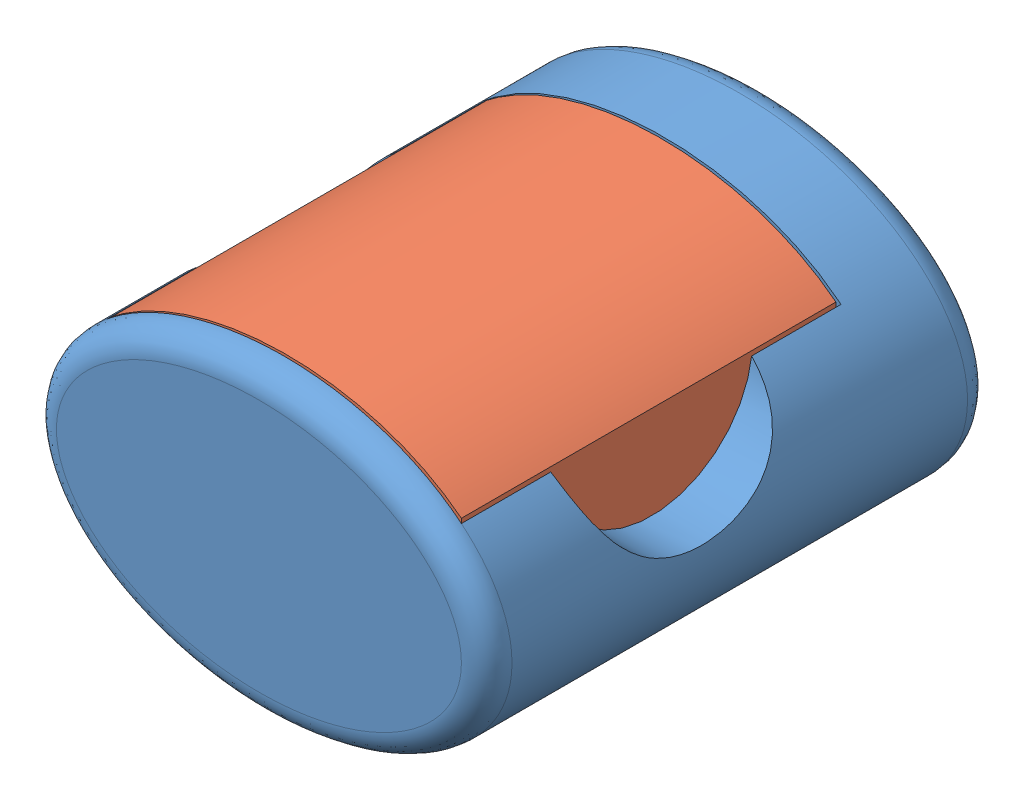
SolidWorks assembly Assem1, configuration Default. Lengths in mm.
Overall size (49.94 34.53 51.77).
31 component instances, 12 part files, 5 mates.
Components (placement in the parent):
- Final Case Bottom-1: Final Case Bottom [Default] at (-38.8329 14.8204 36.3325) size (49.94 34.53 51.77)
- Part2^Assem1-1: Part2^Assem1 [Default] at origin (virtual)
- Final Case Top-1: Final Case Top [Default] at (-38.8329 14.8204 36.3325) size (37.59 19.69 37.59)
- Final Flashlight PCB-1: Final Flashlight PCB [Default] at (-52.8029 8.7956 0.7725) x (1 0 0) z (0 -1 0) size (27.94 31.75 17.34)
  - Board_1-1: Board_1 [Default] at origin size (27.94 31.75 0.41)
  - Imported_1-1: Imported_1 [Default] at origin size (27.76 30.96 17.34)
    - keystone-PN1025-7_1-1: keystone-PN1025-7_1 [Default] at (13.9955 14.1608 -2.9515) x (1 0 0) z (0 1 0) size (27.76 17.34 30.96)
  - U1_1-1: U1_1 [Default] at origin size (3.01 2.91 1.23)
    - SOT23-3_1-1: SOT23-3_1 [Default] at (13.9939 25.8873 0) x (0 -1 0) z (0 0 1) size (2.91 3.01 1.23)
    - 5808185472-1: 5808185472 [Default] at (14.097 26.162 0) size (0.25 0.25 0.25)
      - Extruded_1-1: Extruded_1 [Default] at origin size (0.25 0.25 0.25)
  - R3_1-1: R3_1 [Default] at origin size (0.95 1.7 0.9)
    - 5808185088-1: 5808185088 [Default] at (18.288 9.767 0) size (0.95 1.7 0.9)
      - Extruded_1_2-1: Extruded_1_2 [Default] at origin size (0.95 1.7 0.9)
  - R2_1-1: R2_1 [Default] at origin size (0.95 1.7 0.9)
    - 5808185088-1: 5808185088 [Default] at (16.129 9.767 0) size (0.95 1.7 0.9)
      - Extruded_1_2-1: Extruded_1_2 [Default] at origin size (0.95 1.7 0.9)
  - R1_1-1: R1_1 [Default] at origin size (0.95 1.7 0.9)
    - 5808185088-1: 5808185088 [Default] at (10.045 9.767 0) size (0.95 1.7 0.9)
      - Extruded_1_2-1: Extruded_1_2 [Default] at origin size (0.95 1.7 0.9)
  - R4_1-1: R4_1 [Default] at origin size (1.7 0.95 0.9)
    - 5808184896-1: 5808184896 [Default] at (18.046 12.827 0) size (1.7 0.95 0.9)
      - Extruded_1_3-1: Extruded_1_3 [Default] at origin size (1.7 0.95 0.9)
  - C2_1-1: C2_1 [Default] at origin size (0.95 1.75 1.3)
    - 5808185280-1: 5808185280 [Default] at (11.303 26.859 0) size (0.95 1.75 1.3)
      - Extruded_1_4-1: Extruded_1_4 [Default] at origin size (0.95 1.75 1.3)
  - C1_1-1: C1_1 [Default] at origin size (1.75 0.95 1.3)
    - 5808184704-1: 5808184704 [Default] at (13.843 22.795 0) size (1.75 0.95 1.3)
      - Extruded_1_5-1: Extruded_1_5 [Default] at origin size (1.75 0.95 1.3)
  - ATTiny85_1-1: ATTiny85_1 [Default] at origin size (8.25 5.36 2.16)
    - 8S2_1-1: 8S2_1 [Default] at (19.4181 20.066 0) x (0 1 0) z (0 0 1) size (8.25 5.36 2.16)
Mates (geometry in assembly coordinates):
- Distance1: distance = 0.254 mm anti-aligned: plane of Final Case Top-1 through (-21.3069 -2.4824 33.5385) normal (1 0 0); plane of Final Case Bottom-1 through (-21.0529 10.1214 33.7925) normal (-1 0 0)
- Distance2: distance = 0.254 mm anti-aligned: plane of Final Case Top-1 through (-56.3589 -2.4824 -4.0535) normal (0 0 -1); plane of Final Case Bottom-1 through (-38.8329 14.8204 -4.3075) normal (0 0 1)
- Distance3: distance = 0.254 mm anti-aligned: plane of Final Case Top-1 through (-38.8329 10.3754 36.3325) normal (0 -1 0); plane of Final Case Bottom-1 through (-38.8329 10.1214 36.3325) normal (0 1 0)
- Concentric1: concentric aligned: circle of Final Case Bottom-1; circle of Final Flashlight PCB-1/Board_1-1
- Concentric2: concentric anti-aligned: circle of Final Case Bottom-1; circle of Final Flashlight PCB-1/Board_1-1
